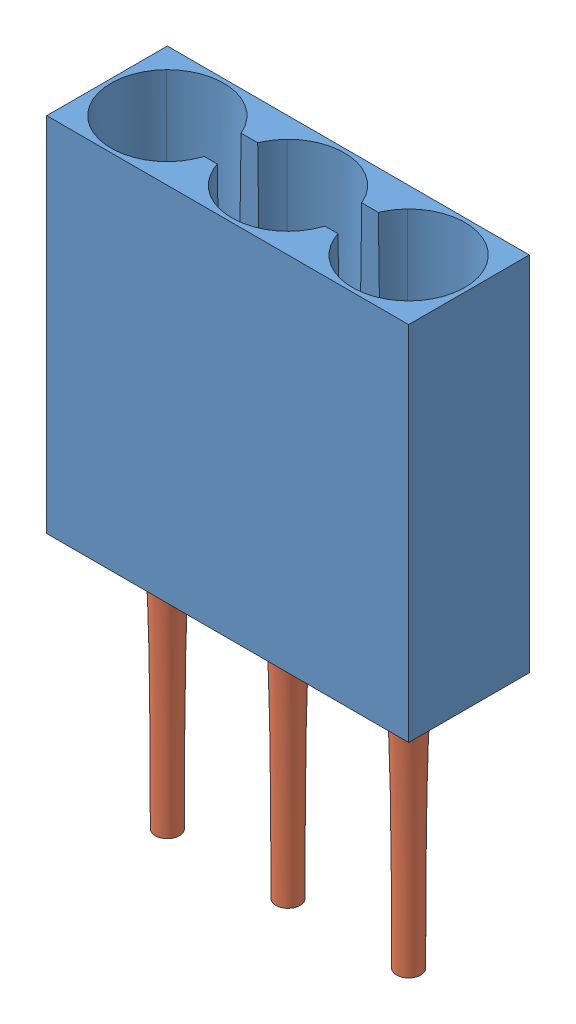
SolidWorks assembly Wider_gap_teeth_together, configuration Default. Lengths in mm.
Overall size (15.49 25.6 7.22).
2 component instances, 2 part files, 3 mates.
Components (placement in the parent):
- cone_base_tall_wider_gap_connected_teeth-1: cone_base_tall_wider_gap_connected_teeth [Default] at origin size (15.49 15 5.52)
- convex_cone-1: convex_cone [Default] at (5 7.5 2.5) x (-0.990587 0 0.136884) z (0.136884 0 0.990587) size (13.91 15 5.37)
Mates (geometry in assembly coordinates):
- Concentric1: concentric: circle of cone_base_tall-1; circle of convex_cone-1
- Concentric2: concentric: circle of cone_base_tall-1; circle of convex_cone-1
- Coincident1: coincident anti-aligned: plane of cone_base_tall-1 through (0 6.5 0) normal (0 1 0); plane of convex_cone-1 through (5 6.5 3.5) normal (0 -1 0)
